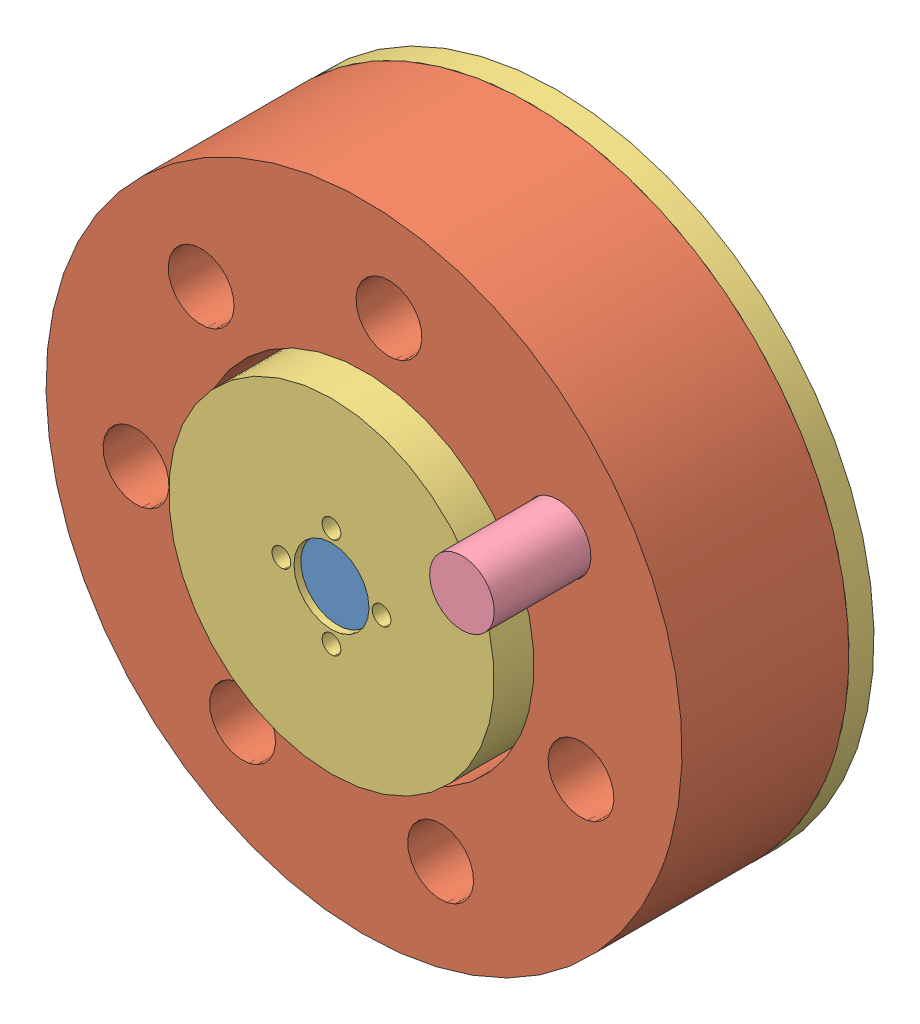
SolidWorks assembly single gyro, configuration Default. Lengths in mm.
Overall size (96.93 96.93 37.69).
4 component instances, 4 part files, 9 mates.
Components (placement in the parent):
- orange motor-1: orange motor [Default] at (11.7926 14.3607 8.0531) size (27.9 27.9 29.34)
- alluminum ring-1: alluminum ring [Default] at (11.7926 14.3607 14.2431) x (0.945036 -0.326968 0) z (0 0 1) size (76.2 76.2 20)
- lower gyro motor adapter-1: lower gyro motor adapter [Default] at (11.7926 14.3607 11.2431) x (1 0 0) z (0 -1 0) size (76.2 26.9 76.2)
- screw-1: screw [Default] at (35.0261 29.0731 20.7431) x (-0.926208 0.377012 0) z (0 0 -1) size (13 13 32.5)
Mates (geometry in assembly coordinates):
- Concentric1: concentric aligned: circle of orange motor-1; circle of lower gyro motor adapter-1
- Concentric2: concentric aligned: circle of orange motor-1; circle of lower gyro motor adapter-1
- Coincident1: coincident anti-aligned: plane of orange motor-1 through (11.7926 14.3607 35.1431) normal (0 0 1); plane of lower gyro motor adapter-1 through (11.7926 14.3607 35.1431) normal (0 0 -1)
- Concentric3: concentric aligned: cylinder of alluminum ring-1 through (11.7926 14.3607 34.2431) axis (0 0 -1) radius 20.375; cylinder of lower gyro motor adapter-1 through (11.7926 14.3607 24.2431) axis (0 0 -1) radius 20
- Coincident2: coincident anti-aligned: plane of alluminum ring-1 through (11.7926 14.3607 14.2431) normal (0 0 -1); plane of lower gyro motor adapter-1 through (11.7926 14.3607 14.2431) normal (0 0 1)
- Coincident3: coincident aligned: circle of ?; circle of lower gyro motor adapter-1
- Concentric4: concentric aligned: circle of lower gyro motor adapter-1; circle of ?
- Concentric5: concentric: cylinder of alluminum ring-1 through (35.0261 29.0731 34.2431) axis (0 0 -1) radius 3.95; cylinder of screw-1 through (35.0261 29.0731 85.5) axis (0 0 -1) radius 3.875
- Coincident4: coincident anti-aligned: plane of alluminum ring-1 through (35.0261 29.0731 20.7431) normal (0 0 -1); plane of screw-1 through (35.0261 29.0731 20.7431) normal (0 0 1)
